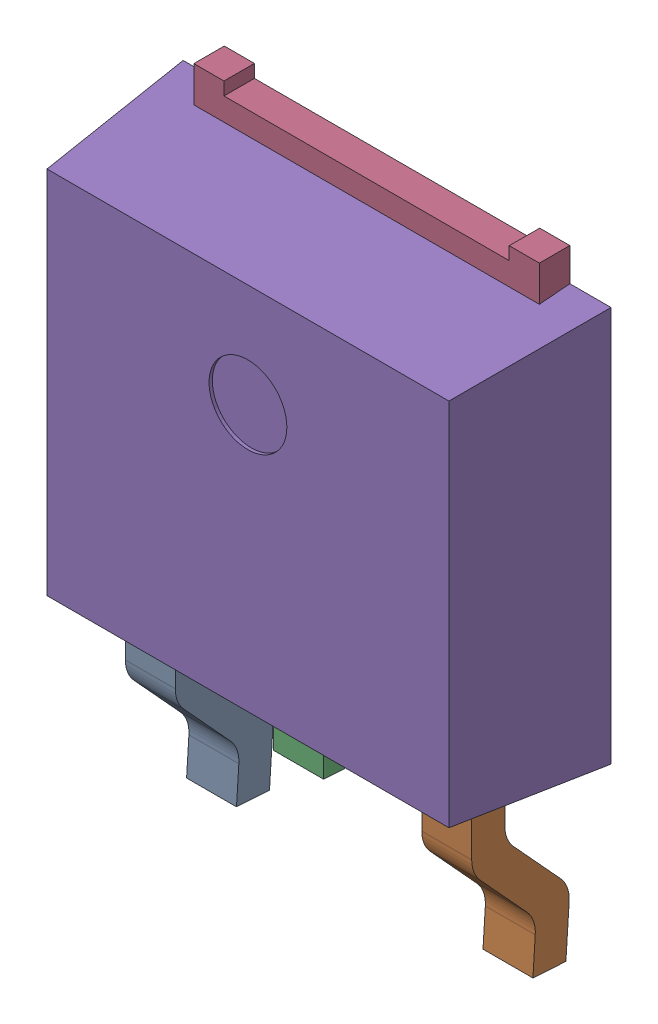
SolidWorks assembly IC9_1.step, configuration Default. Lengths in mm.
Overall size (6.6 9.53 2.3).
3 component instances, 2 part files, 0 mates.
Components (placement in the parent):
- 6348793488_1.step-11: 6348793488_1.step [Default] at (411.867 301.671 0) x (1 0 0) z (0 0 1) size (6.6 9.53 2.3)
  - Linear Pattern 01_1.step-21: Linear Pattern 01_1.step [Default] at origin size (5.34 3.53 1.5)
  - Open CASCADE STEP translator 7.5 5.121.1.2_1.step-21: Open CASCADE STEP translator 7.5 5.121.1.2_1.step [Default] at origin size (6.6 6.61 2.3)
